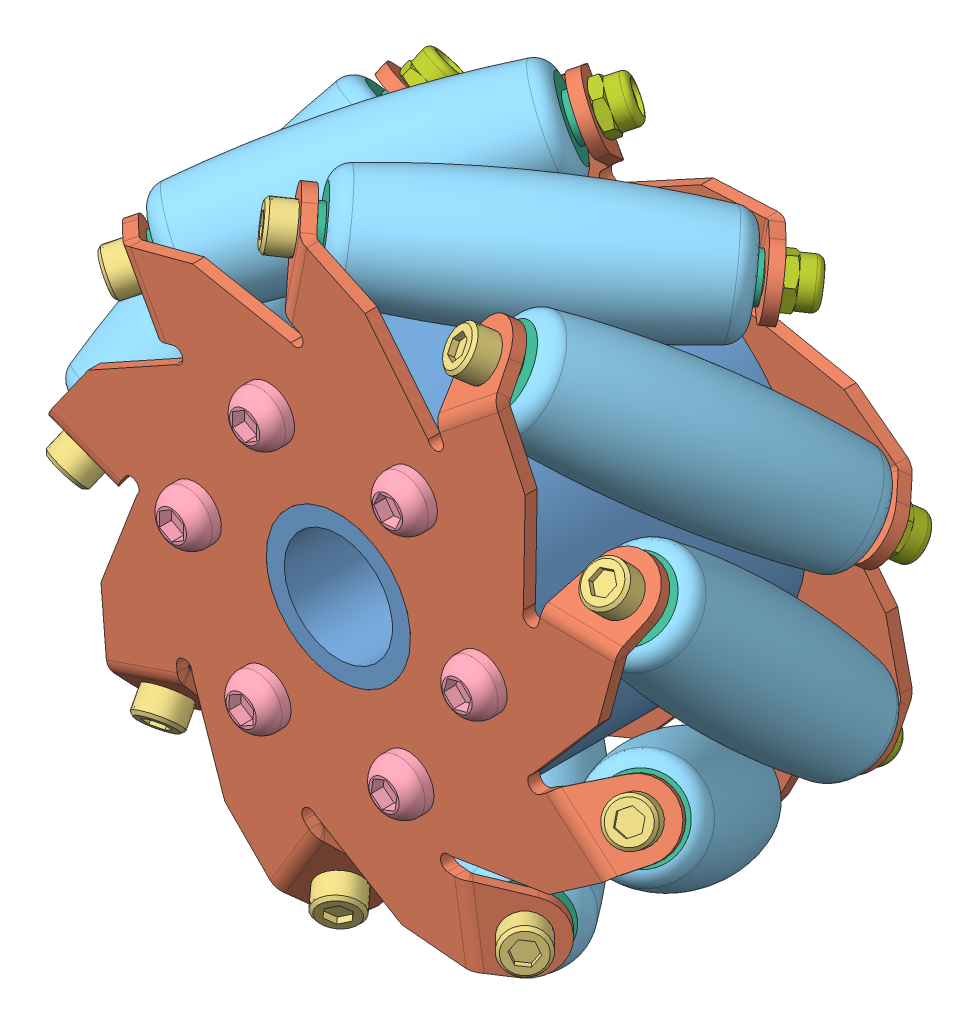
SolidWorks assembly Mecanum Wheel Assembly, configuration Default. Lengths in mm.
Overall size (139.25 139.19 58).
60 component instances, 7 part files, 41 mates.
Components (placement in the parent):
- Shaft-1: Shaft [Default] at (30.1029 34.2024 40.0243) size (60 60 50)
- Body-1: Body [Default] at (30.1029 34.2024 17.0243) x (0.999612 -0.027853 0) z (0 0 1) size (101.45 101.64 10.08)
- Body-2: Body [Default] at (30.1029 34.2024 63.0243) x (-0.512013 -0.858977 0) z (0 0 -1) size (101.45 101.64 10.08)
- Bolt (M3)-1: Bolt (M3) [Default] at (48.0978 78.3074 63.2345) x (0.443104 -0.551052 -0.707107) z (0.648805 -0.347188 0.677135) size (66 7 7)
- Bolt (M5)-1: Bolt (M5) [Default] at (42.2633 54.6031 69.0243) x (0 0 -1) z (0.099021 -0.995085 0) size (44 8.6 8.6)
- Roller-1: Roller [Default] at (62.5307 60.3583 39.9719) x (0.443104 -0.551052 -0.707107) z (0.696949 -0.284351 0.658336) size (51 19.45 19.45)
- Roller Bracket-1: Roller Bracket [Default] at (51.2316 74.4101 58.0031) x (-0.428834 0.562376 -0.706989) z (-0.787248 -0.616501 -0.012881) size (12 5 12)
- Roller Bracket-2: Roller Bracket [Default] at (73.8299 46.3065 21.9407) x (0.563844 0.784529 -0.258058) z (0.696949 -0.284351 0.658336) size (12 5 12)
- torque nut 08_iso-1: torque nut 08_iso [ISO 10511-M4-N] at (76.134 43.441 18.2637) x (0.449747 0.818969 -0.356396) z (0.443104 -0.551052 -0.707107) size (7 8.08 5)
- Roller Bracket-3: Roller Bracket [Default] at (55.8194 71.5818 21.9407) x (-0.072356 0.963416 -0.258058) z (0.716672 0.230165 0.658336) size (12 5 12)
- Roller Bracket-4: Roller Bracket [Default] at (25.7758 79.3669 21.9407) x (-0.6747 0.69151 -0.258058) z (0.401055 0.636984 0.658336) size (12 5 12)
- Roller Bracket-5: Roller Bracket [Default] at (-2.243 66.019 21.9407) x (-0.961344 0.096039 -0.258058) z (-0.102219 0.745752 0.658336) size (12 5 12)
- Roller Bracket-6: Roller Bracket [Default] at (-15.1268 37.7837 21.9407) x (-0.798165 -0.54437 -0.258058) z (-0.557664 0.505574 0.658336) size (12 5 12)
- Roller Bracket-7: Roller Bracket [Default] at (-6.8471 7.8727 21.9407) x (-0.261516 -0.930062 -0.258058) z (-0.752172 0.028832 0.658336) size (12 5 12)
- Roller Bracket-8: Roller Bracket [Default] at (18.7219 -9.7183 21.9407) x (0.3975 -0.880568 -0.258058) z (-0.59473 -0.4614 0.658336) size (12 5 12)
- Roller Bracket-9: Roller Bracket [Default] at (49.6163 -6.7584 21.9407) x (0.870521 -0.419046 -0.258058) z (-0.159007 -0.735738 0.658336) size (12 5 12)
- Roller Bracket-10: Roller Bracket [Default] at (71.3801 15.3675 21.9407) x (0.936215 0.238552 -0.258058) z (0.351117 -0.665816 0.658336) size (12 5 12)
- torque nut 08_iso-3: torque nut 08_iso [ISO 10511-M4-N] at (59.4263 70.8678 18.2637) x (-0.181897 0.916458 -0.356396) z (0.693647 -0.137309 -0.707107) size (7 8.08 5)
- torque nut 08_iso-4: torque nut 08_iso [ISO 10511-M4-N] at (28.9979 81.1384 18.2637) x (-0.728429 0.585127 -0.356396) z (0.619625 0.340683 -0.707107) size (7 8.08 5)
- torque nut 08_iso-5: torque nut 08_iso [ISO 10511-M4-N] at (-0.9135 69.4471 18.2637) x (-0.934121 -0.019992 -0.356396) z (0.255673 0.659266 -0.707107) size (7 8.08 5)
- torque nut 08_iso-6: torque nut 08_iso [ISO 10511-M4-N] at (-16.3119 41.2645 18.2637) x (-0.702728 -0.615756 -0.356396) z (-0.227911 0.66937 -0.707107) size (7 8.08 5)
- torque nut 08_iso-7: torque nut 08_iso [ISO 10511-M4-N] at (-9.9923 9.7773 18.2637) x (-0.14252 -0.923401 -0.356396) z (-0.604853 0.366269 -0.707107) size (7 8.08 5)
- torque nut 08_iso-8: torque nut 08_iso [ISO 10511-M4-N] at (15.0883 -10.281 18.2637) x (0.484374 -0.798977 -0.356396) z (-0.698777 -0.108213 -0.707107) size (7 8.08 5)
- torque nut 08_iso-9: torque nut 08_iso [ISO 10511-M4-N] at (47.1944 -9.5251 18.2637) x (0.884624 -0.300702 -0.356396) z (-0.465736 -0.532062 -0.707107) size (7 8.08 5)
- torque nut 08_iso-10: torque nut 08_iso [ISO 10511-M4-N] at (71.3033 11.6914 18.2637) x (0.870949 0.338275 -0.356396) z (-0.014772 -0.706952 -0.707107) size (7 8.08 5)
- Roller-2: Roller [Default] at (38.1314 75.0832 39.9719) x (0.693647 -0.137309 -0.707107) z (0.716672 0.230165 0.658336) size (51 19.45 19.45)
- Roller-3: Roller [Default] at (9.9754 70.6794 39.9719) x (0.619625 0.340683 -0.707107) z (0.401055 0.636984 0.658336) size (51 19.45 19.45)
- Roller-4: Roller [Default] at (-8.7627 49.2077 39.9719) x (0.255673 0.659266 -0.707107) z (-0.102219 0.745752 0.658336) size (51 19.45 19.45)
- Roller-5: Roller [Default] at (-9.3151 20.7148 39.9719) x (-0.227911 0.66937 -0.707107) z (-0.557664 0.505574 0.658336) size (51 19.45 19.45)
- Roller-6: Roller [Default] at (8.5766 -1.4671 39.9719) x (-0.604853 0.366269 -0.707107) z (-0.752172 0.028832 0.658336) size (51 19.45 19.45)
- Roller-7: Roller [Default] at (36.5408 -6.9589 39.9719) x (-0.698777 -0.108213 -0.707107) z (-0.59473 -0.4614 0.658336) size (51 19.45 19.45)
- Roller-8: Roller [Default] at (61.4925 6.8092 39.9719) x (-0.465736 -0.532062 -0.707107) z (-0.159007 -0.735738 0.658336) size (51 19.45 19.45)
- Roller-9: Roller [Default] at (71.7568 33.3948 39.9719) x (-0.014772 -0.706952 -0.707107) z (0.351117 -0.665816 0.658336) size (51 19.45 19.45)
- Roller Bracket-11: Roller Bracket [Default] at (20.4434 78.5845 58.0031) x (-0.689995 0.155156 -0.706989) z (-0.206788 -0.978301 -0.012881) size (12 5 12)
- Roller Bracket-12: Roller Bracket [Default] at (-5.825 61.992 58.0031) x (-0.628299 -0.324664 -0.706989) z (0.470431 -0.882343 -0.012881) size (12 5 12)
- Roller Bracket-13: Roller Bracket [Default] at (-15.2823 32.3964 58.0031) x (-0.272615 -0.652569 -0.706989) z (0.92753 -0.373526 -0.012881) size (12 5 12)
- Roller Bracket-14: Roller Bracket [Default] at (-3.5033 3.6458 58.0031) x (0.210628 -0.675131 -0.706989) z (0.950627 0.310067 -0.012881) size (12 5 12)
- Roller Bracket-15: Roller Bracket [Default] at (24.0004 -10.807 58.0031) x (0.595316 -0.381791 -0.706989) z (0.528916 0.848577 -0.012881) size (12 5 12)
- Roller Bracket-16: Roller Bracket [Default] at (54.3596 -4.1995 58.0031) x (0.701449 0.090193 -0.706989) z (-0.140282 0.990028 -0.012881) size (12 5 12)
- Roller Bracket-17: Roller Bracket [Default] at (73.3688 20.3767 58.0031) x (0.479366 0.519975 -0.706989) z (-0.74384 0.668234 -0.012881) size (12 5 12)
- Roller Bracket-18: Roller Bracket [Default] at (72.1335 51.4221 58.0031) x (0.032983 0.706455 -0.706989) z (-0.999347 0.033766 -0.012881) size (12 5 12)
- Bolt (M3)-2: Bolt (M3) [Default] at (15.5376 79.5556 63.2345) x (0.693647 -0.137309 -0.707107) z (0.720182 0.151083 0.677135) size (66 7 7)
- Bolt (M3)-3: Bolt (M3) [Default] at (-10.2073 59.5826 63.2345) x (0.619625 0.340683 -0.707107) z (0.454577 0.57866 0.677135) size (66 7 7)
- Bolt (M3)-4: Bolt (M3) [Default] at (-17.0906 27.7338 63.2345) x (0.255673 0.659266 -0.707107) z (-0.023729 0.735476 0.677135) size (66 7 7)
- Bolt (M3)-5: Bolt (M3) [Default] at (-1.8915 -1.0882 63.2345) x (-0.227911 0.66937 -0.707107) z (-0.490932 0.548154 0.677135) size (66 7 7)
- Bolt (M3)-6: Bolt (M3) [Default] at (28.2781 -13.3974 63.2345) x (-0.604853 0.366269 -0.707107) z (-0.728423 0.104345 0.677135) size (66 7 7)
- Bolt (M3)-7: Bolt (M3) [Default] at (59.3016 -3.4341 63.2345) x (-0.698777 -0.108213 -0.707107) z (-0.625076 -0.388288 0.677135) size (66 7 7)
- Bolt (M3)-8: Bolt (M3) [Default] at (76.6627 24.1397 63.2345) x (-0.465736 -0.532062 -0.707107) z (-0.229249 -0.699237 0.677135) size (66 7 7)
- Bolt (M3)-9: Bolt (M3) [Default] at (72.2379 56.4219 63.2345) x (-0.014772 -0.706952 -0.707107) z (0.273846 -0.683005 0.677135) size (66 7 7)
- Bolt (M5)-2: Bolt (M5) [Default] at (53.8506 33.8716 69.0243) x (0 0 -1) z (0.255542 -0.966798 0) size (44 8.6 8.6)
- Bolt (M5)-4: Bolt (M5) [Default] at (41.6903 13.4709 69.0243) x (0 0 -1) z (0.376566 -0.92639 0) size (44 8.6 8.6)
- Bolt (M5)-6: Bolt (M5) [Default] at (17.9426 13.8017 69.0243) x (0 0 -1) z (0.461278 -0.887256 0) size (44 8.6 8.6)
- Bolt (M5)-8: Bolt (M5) [Default] at (6.3552 34.5332 69.0243) x (0 0 -1) z (0.508895 -0.860829 0) size (44 8.6 8.6)
- Bolt (M5)-10: Bolt (M5) [Default] at (18.5156 54.9339 69.0243) x (0 0 -1) z (0.517245 -0.855838 0) size (44 8.6 8.6)
- Bolt (M5)-12: Bolt (M5) [Default] at (42.5462 54.4317 11.0243) x (0 0 1) z (-0.583297 -0.812259 0) size (44 8.6 8.6)
- Bolt (M5)-14: Bolt (M5) [Default] at (18.8054 55.0932 11.0243) x (0 0 1) z (-0.433388 -0.901207 0) size (44 8.6 8.6)
- Bolt (M5)-16: Bolt (M5) [Default] at (6.3622 34.8639 11.0243) x (0 0 1) z (-0.270311 -0.962773 0) size (44 8.6 8.6)
- Bolt (M5)-18: Bolt (M5) [Default] at (17.6597 13.973 11.0243) x (0 0 1) z (-0.099021 -0.995085 0) size (44 8.6 8.6)
- Bolt (M5)-20: Bolt (M5) [Default] at (41.4004 13.3115 11.0243) x (0 0 1) z (0.075278 -0.997163 0) size (44 8.6 8.6)
- Bolt (M5)-22: Bolt (M5) [Default] at (53.8437 33.5409 11.0243) x (0 0 1) z (0.24729 -0.968941 0) size (44 8.6 8.6)
Mates (geometry in assembly coordinates):
- Concentric1: concentric anti-aligned: circle of Shaft-1; circle of Body-2
- Coincident1: coincident anti-aligned: plane of Shaft-1 through (30.1029 34.2024 63.0243) normal (0 0 1); plane of Body-2 through (-4.3323 32.9855 63.0243) normal (0 0 -1)
- Concentric2: concentric aligned: circle of Shaft-1; circle of Body-1
- Concentric3: concentric aligned: cylinder of Body-2 through (42.2633 54.6031 65.0243) axis (0 0 -1) radius 2.5; cylinder of Shaft-1 through (42.2633 54.6031 63.0243) axis (0 0 -1) radius 2.5
- Parallel1: parallel anti-aligned: plane of Body-1 through (53.7956 57.383 -1.0134) normal (-0.443104 0.551052 0.707107); plane of Body-2 through (-2.937 31.2501 59.4407) normal (0.443104 -0.551052 -0.707107)
- Concentric4: concentric aligned: circle of Shaft-1; circle of Body-1
- Coincident2: coincident anti-aligned: plane of Shaft-1 through (30.1029 34.2024 17.0243) normal (0 0 -1); plane of Body-1 through (49.5788 62.627 17.0243) normal (0 0 1)
- Concentric5: concentric anti-aligned: cylinder of Roller-1 through (72.0575 48.5107 24.7691) axis (0.443104 -0.551052 -0.707107) radius 4; circle of Roller Bracket-2
- Coincident3: coincident anti-aligned: plane of Roller-1 through (72.9437 47.4086 23.3549) normal (0.443104 -0.551052 -0.707107); plane of Roller Bracket-2 through (72.9437 47.4086 23.3549) normal (-0.443104 0.551052 0.707107)
- Concentric6: concentric aligned: circle of Roller-1; circle of Roller Bracket-1
- Coincident4: coincident anti-aligned: plane of Roller-1 through (52.1178 73.308 56.5889) normal (-0.443104 0.551052 0.707107); plane of Roller Bracket-1 through (52.1178 73.308 56.5889) normal (0.443104 -0.551052 -0.707107)
- Concentric7: concentric anti-aligned: circle of Body-1; circle of Roller Bracket-2
- Distance1: distance = 0.25 mm anti-aligned: plane of Body-1 through (53.7956 57.383 -1.0134) normal (-0.443104 0.551052 0.707107); plane of Roller Bracket-2 through (74.273 45.7554 21.2336) normal (0.443104 -0.551052 -0.707107)
- Concentric8: concentric anti-aligned: cylinder of Body-2 through (49.8702 76.1032 60.4061) axis (0.443104 -0.551052 -0.707107) radius 2; cylinder of Bolt (M3)-1 through (48.0978 78.3074 63.2345) axis (-0.443104 0.551052 0.707107) radius 2
- Coincident6: coincident anti-aligned: plane of Body-2 through (-3.8232 32.3522 60.8549) normal (-0.443104 0.551052 0.707107); plane of Bolt (M3)-1 through (52.0354 78.759 59.6932) normal (0.443104 -0.551052 -0.707107)
- Concentric9: concentric anti-aligned: cylinder of Body-1 through (75.27 44.5155 19.6426) axis (-0.443104 0.551052 0.707107) radius 2; cylinder of torque nut 08_iso-1 through (84.5752 32.9434 4.7933) axis (0.443104 -0.551052 -0.707107) radius 2
- Coincident7: coincident anti-aligned: plane of Body-1 through (54.6818 56.2808 -2.4276) normal (0.443104 -0.551052 -0.707107); plane of torque nut 08_iso-1 through (78.4041 43.8685 22.1108) normal (-0.443104 0.551052 0.707107)
- Concentric11: concentric anti-aligned: cylinder of Body-2 through (42.2633 54.6031 65.0243) axis (0 0 -1) radius 2.5; cylinder of Bolt (M5)-1 through (42.2633 54.6031 69.0243) axis (0 0 1) radius 2.5
- Coincident8: coincident anti-aligned: plane of Body-2 through (-4.3323 32.9855 65.0243) normal (0 0 1); plane of Bolt (M5)-1 through (46.5421 55.0289 65.0243) normal (0 0 -1)
- Concentric12: concentric anti-aligned: cylinder of Body-2 through (53.8506 33.8716 65.0243) axis (0 0 -1) radius 2.5; cylinder of Bolt (M5)-2 through (53.8506 33.8716 69.0243) axis (0 0 1) radius 2.5
- Coincident9: coincident anti-aligned: plane of Body-2 through (-4.3323 32.9855 65.0243) normal (0 0 1); plane of Bolt (M5)-2 through (58.0079 34.9704 65.0243) normal (0 0 -1)
- Concentric13: concentric anti-aligned: cylinder of Body-2 through (41.6903 13.4709 65.0243) axis (0 0 -1) radius 2.5; cylinder of Bolt (M5)-4 through (41.6903 13.4709 69.0243) axis (0 0 1) radius 2.5
- Coincident10: coincident anti-aligned: plane of Body-2 through (-4.3323 32.9855 65.0243) normal (0 0 1); plane of Bolt (M5)-4 through (45.6738 15.0901 65.0243) normal (0 0 -1)
- Concentric14: concentric anti-aligned: cylinder of Body-2 through (17.9426 13.8017 65.0243) axis (0 0 -1) radius 2.5; cylinder of Bolt (M5)-6 through (17.9426 13.8017 69.0243) axis (0 0 1) radius 2.5
- Coincident11: coincident anti-aligned: plane of Body-2 through (-4.3323 32.9855 65.0243) normal (0 0 1); plane of Bolt (M5)-6 through (21.7578 15.7851 65.0243) normal (0 0 -1)
- Concentric15: concentric anti-aligned: cylinder of Body-2 through (6.3552 34.5332 65.0243) axis (0 0 -1) radius 2.5; cylinder of Bolt (M5)-8 through (6.3552 34.5332 69.0243) axis (0 0 1) radius 2.5
- Coincident12: coincident anti-aligned: plane of Body-2 through (-4.3323 32.9855 65.0243) normal (0 0 1); plane of Bolt (M5)-8 through (10.0568 36.7214 65.0243) normal (0 0 -1)
- Concentric16: concentric anti-aligned: cylinder of Body-2 through (18.5156 54.9339 65.0243) axis (0 0 -1) radius 2.5; cylinder of Bolt (M5)-10 through (18.5156 54.9339 69.0243) axis (0 0 1) radius 2.5
- Coincident13: coincident anti-aligned: plane of Body-2 through (-4.3323 32.9855 65.0243) normal (0 0 1); plane of Bolt (M5)-10 through (22.1957 57.158 65.0243) normal (0 0 -1)
- Concentric17: concentric anti-aligned: cylinder of Body-1 through (42.5462 54.4317 15.0243) axis (0 0 1) radius 2.5; cylinder of Bolt (M5)-12 through (42.5462 54.4317 11.0243) axis (0 0 -1) radius 2.5
- Coincident14: coincident anti-aligned: plane of Body-1 through (49.5788 62.627 15.0243) normal (0 0 -1); plane of Bolt (M5)-12 through (39.0535 56.9399 15.0243) normal (0 0 1)
- Concentric18: concentric anti-aligned: cylinder of Body-1 through (18.8054 55.0932 15.0243) axis (0 0 1) radius 2.5; cylinder of Bolt (M5)-14 through (18.8054 55.0932 11.0243) axis (0 0 -1) radius 2.5
- Coincident15: coincident anti-aligned: plane of Body-1 through (49.5788 62.627 15.0243) normal (0 0 -1); plane of Bolt (M5)-14 through (14.9302 56.9568 15.0243) normal (0 0 1)
- Concentric19: concentric anti-aligned: cylinder of Body-1 through (6.3622 34.8639 15.0243) axis (0 0 1) radius 2.5; cylinder of Bolt (M5)-16 through (6.3622 34.8639 11.0243) axis (0 0 -1) radius 2.5
- Coincident16: coincident anti-aligned: plane of Body-1 through (49.5788 62.627 15.0243) normal (0 0 -1); plane of Bolt (M5)-16 through (2.2222 36.0262 15.0243) normal (0 0 1)
- Concentric20: concentric anti-aligned: cylinder of Body-1 through (17.6597 13.973 15.0243) axis (0 0 1) radius 2.5; cylinder of Bolt (M5)-18 through (17.6597 13.973 11.0243) axis (0 0 -1) radius 2.5
- Coincident17: coincident anti-aligned: plane of Body-1 through (49.5788 62.627 15.0243) normal (0 0 -1); plane of Bolt (M5)-18 through (13.3808 14.3988 15.0243) normal (0 0 1)
- Concentric21: concentric anti-aligned: cylinder of Body-1 through (41.4004 13.3115 15.0243) axis (0 0 1) radius 2.5; cylinder of Bolt (M5)-20 through (41.4004 13.3115 11.0243) axis (0 0 -1) radius 2.5
- Coincident18: coincident anti-aligned: plane of Body-1 through (49.5788 62.627 15.0243) normal (0 0 -1); plane of Bolt (M5)-20 through (37.1126 12.9878 15.0243) normal (0 0 1)
- Concentric22: concentric anti-aligned: cylinder of Body-1 through (53.8437 33.5409 15.0243) axis (0 0 1) radius 2.5; cylinder of Bolt (M5)-22 through (53.8437 33.5409 11.0243) axis (0 0 -1) radius 2.5
- Coincident19: coincident anti-aligned: plane of Body-1 through (49.5788 62.627 15.0243) normal (0 0 -1); plane of Bolt (M5)-22 through (49.6773 32.4775 15.0243) normal (0 0 1)
